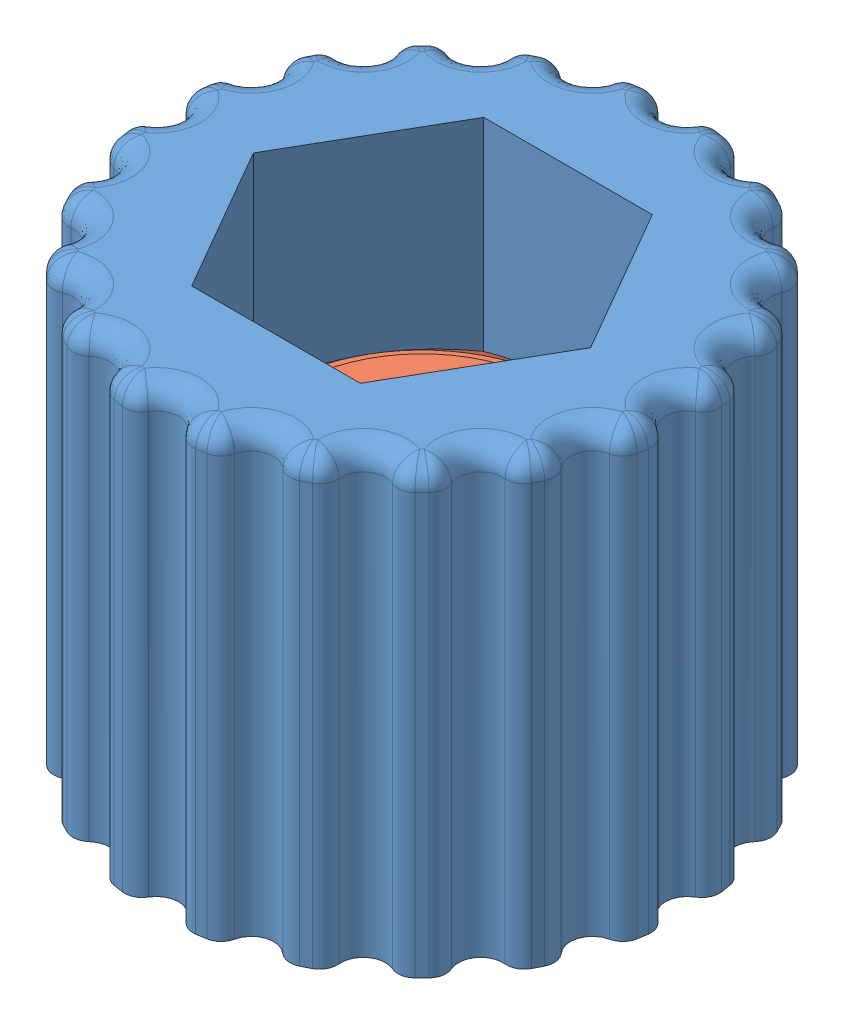
SolidWorks assembly M8_Knob_Assembly_P, configuration Default. Lengths in mm.
Overall size (23.87 20.07 23.87).
2 component instances, 2 part files, 3 mates.
Components (placement in the parent):
- M8_Knob_P-1: M8_Knob_P [Default] at (5.3677 2.3842 20.2202) size (23.87 20.07 23.87)
- M8 x 1.25 Hex Nut-1: M8 x 1.25 Hex Nut [90592A022] at (5.3677 10.6342 20.2202) x (0 0 1) z (-1 0 0) size (13 7.48 15.01)
Mates (geometry in assembly coordinates):
- Concentric1: concentric: circle of M8_Knob_P-1; circle of M8 x 1.25 Hex Nut-1
- Parallel1: parallel: plane of M8_Knob_P-1 through (1.5572 7.3842 13.6202) normal (0.866025 0 0.5); plane of M8 x 1.25 Hex Nut-1 through (1.6149 13.8842 13.7202) normal (-0.866025 0 -0.5)
- Coincident2: coincident anti-aligned: plane of M8_Knob_P-1 through (5.3677 7.3842 20.2202) normal (0 1 0); plane of M8 x 1.25 Hex Nut-1 through (9.1205 7.3842 13.7202) normal (0 -1 0)
